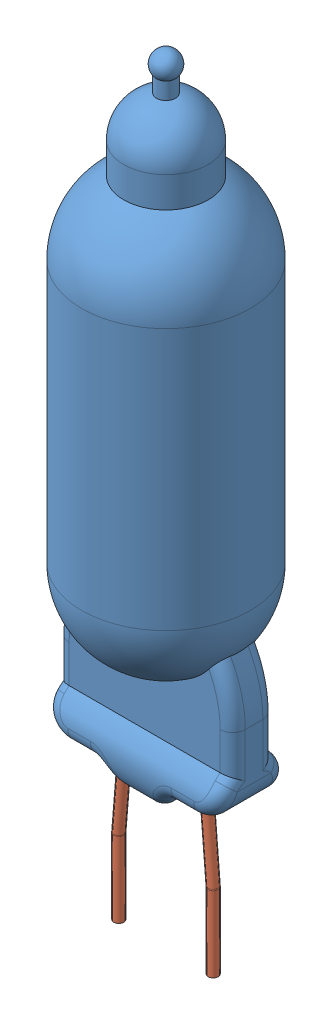
SolidWorks assembly NX-SZP-IN3-v01, configuration Default. Lengths in mm.
Overall size (7 30.9 6.7).
7 component instances, 6 part files, 17 mates.
Components (placement in the parent):
- NX-SZP-IN3-01-v01-1: NX-SZP-IN3-01-v01 [Default] at origin size (7 25.5 6.7)
- NX-SZP-IN3-02-v01-1: NX-SZP-IN3-02-v01 [Default] at (-1.8758 -15.45 0) x (1 -0.000085 0) z (0 0 1) size (1.42 15.52 0.4)
- NX-SZP-IN3-02-v01-2: NX-SZP-IN3-02-v01 [Default] at (1.8758 -15.45 0) x (-1 -0.000085 0) z (0 0 -1) size (1.42 15.52 0.4)
- NX-SZP-IN3-03-v01-1: NX-SZP-IN3-03-v01 [Default] at (0 -0.3 0) size (4.7 0.5 4.7)
- NX-SZP-IN3-04-v01-1: NX-SZP-IN3-04-v01 [Default] at (0 0.45 0) x (0.944255 0 -0.329215) z (0.329215 0 0.944255) size (4.5 9.5 2.12)
- NX-SZP-IN3-05-v01-1: NX-SZP-IN3-05-v01 [Default] at (-0.4793 0.15 -1.3869) x (0.944255 0 -0.329215) z (0.329215 0 0.944255) size (4.4 6.2 0.9)
- NX-SZP-IN3-06-v01-1: NX-SZP-IN3-06-v01 [Default] at origin size (3.26 1.42 2.06)
Mates (geometry in assembly coordinates):
- Coincident1: coordinate: point of ?
- Coincident2: coincident: plane of ? through (0 0 0) normal (0 0 1); plane of NX-SZP-IN3-02-v01-1 through (-1.8758 -15.45 0) normal (0 0 1)
- Concentric1: concentric: cylinder of ? through (-1.2429 -7.6738 0) axis (0.081327 0.996687 0) radius 0.2; cylinder of NX-SZP-IN3-02-v01-1 through (-0.8575 -2.9508 0) axis (-0.081327 -0.996687 0) radius 0.2
- Distance2: distance = 3.4 mm: unknown of NX-SZP-IN3-02-v01-1; plane of ? through (-1.25 -12.05 -1.401) normal (0 -1 0)
- Coincident3: coincident: plane of assembly through (0 0 0) normal (0 0 1); plane of NX-SZP-IN3-02-v01-2 through (1.8758 -15.45 0) normal (0 0 -1); plane of assembly
- Concentric2: concentric: cylinder of ? through (1.2429 -7.6738 0) axis (-0.081327 0.996687 0) radius 0.2; cylinder of NX-SZP-IN3-02-v01-2 through (0.8575 -2.9508 0) axis (0.081327 -0.996687 0) radius 0.2
- Distance3: distance = 3.4 mm: unknown of NX-SZP-IN3-02-v01-2; plane of ? through (1.25 -12.05 -1.401) normal (0 -1 0)
- Coincident4: coincident: plane of assembly through (0 0 0) normal (0 0 1); plane of NX-SZP-IN3-03-v01-1 through (0 -0.3 0) normal (0 0 1); plane of assembly
- Coincident5: coincident: plane of assembly through (0 0 0) normal (1 0 0); plane of NX-SZP-IN3-03-v01-1 through (0 -0.3 0) normal (1 0 0); plane of assembly
- Distance4: distance = 11.5 mm: plane of NX-SZP-IN3-03-v01-1 through (0.8309 -0.55 0.8309) normal (0 -1 0); plane of ? through (-1.25 -12.05 -1.401) normal (0 -1 0)
- Concentric3: concentric: cylinder of assembly; cylinder of assembly; cylinder of NX-SZP-IN3-03-v01-1 through (1.85 -0.551 0) axis (0 1 0) radius 0.25; cylinder of NX-SZP-IN3-04-v01-1 through (1.85 -0.05 0) axis (0 -1 0) radius 0.25
- Concentric5: concentric: cylinder of assembly; cylinder of assembly; cylinder of NX-SZP-IN3-03-v01-1 through (-1.85 -0.551 0) axis (0 1 0) radius 0.25; cylinder of NX-SZP-IN3-04-v01-1 through (-1.85 -0.05 0) axis (0 -1 0) radius 0.25
- Distance6: distance = 0.25 mm: plane of assembly; cylinder of assembly; plane of NX-SZP-IN3-03-v01-1 through (0.8309 -0.05 0.8309) normal (0 1 0); cylinder of NX-SZP-IN3-04-v01-1 through (-1.1561 0.45 0.494) axis (0.986764 0 -0.162162) radius 0.25
- Concentric6: concentric: cylinder of assembly; cylinder of assembly; cylinder of NX-SZP-IN3-03-v01-1 through (-0.925 -0.551 -1.6021) axis (0 1 0) radius 0.25; cylinder of NX-SZP-IN3-05-v01-1 through (-0.925 -1.85 -1.6021) axis (0 1 0) radius 0.25
- Parallel3: parallel: plane of assembly; plane of assembly; plane of NX-SZP-IN3-04-v01-1 through (0.1481 0.45 0.4249) normal (0.329215 0 0.944255); plane of NX-SZP-IN3-05-v01-1 through (-0.4793 0.15 -1.3869) normal (0.329215 0 0.944255)
- Distance7: distance = 0.45 mm: plane of assembly; plane of assembly; plane of NX-SZP-IN3-05-v01-1 through (-0.4793 0.15 -1.3869) normal (0 1 0); plane of NX-SZP-IN3-03-v01-1 through (0 -0.3 0) normal (0 1 0)
- Coincident6: coordinate: unknown of ?
